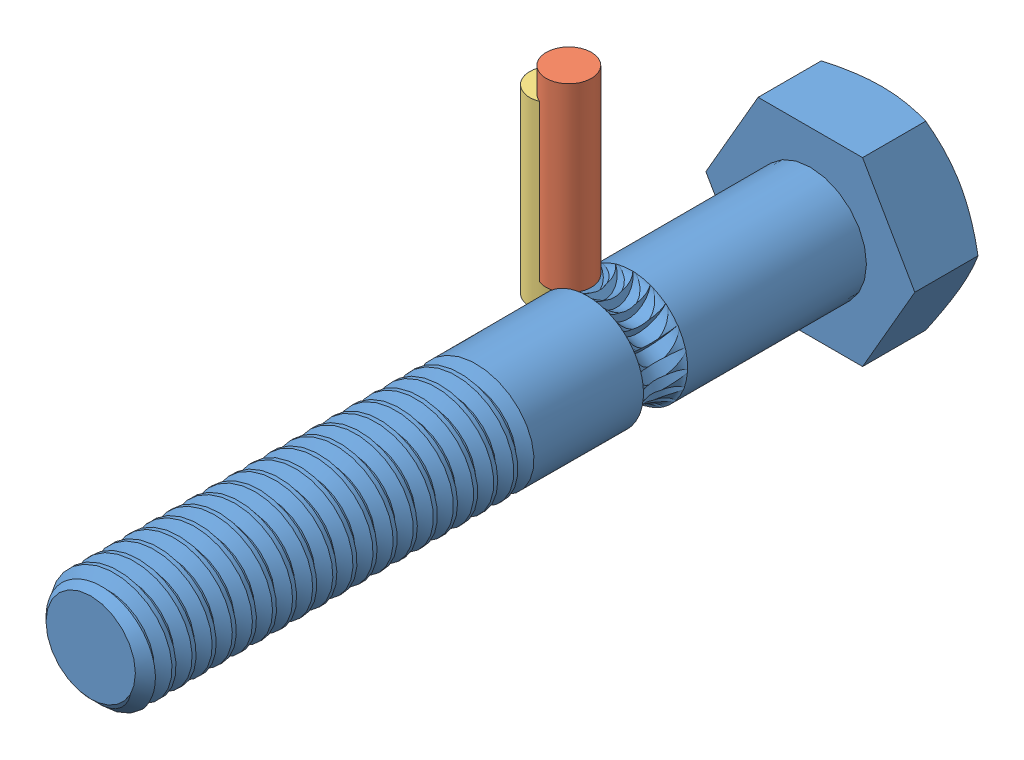
SolidWorks assembly HobbedBoltCutting, configuration Default. Lengths in mm.
Overall size (14.66 22.1 56.13).
3 component instances, 3 part files, 3 mates.
Components (placement in the parent):
- HobbedBolt-Model-1: HobbedBolt-Model [Default] at origin size (14.66 12.7 56.13)
- Waist Cutter^HobbedBoltCutting-1: Waist Cutter^HobbedBoltCutting [Default] at origin size (3.17 12.7 3.18) (virtual)
- Tooth Cutter^HobbedBoltCutting-1: Tooth Cutter^HobbedBoltCutting [Default] at origin size (3.17 12.7 3.18) (virtual)
Mates (geometry in assembly coordinates):
- Coincident1: coincident aligned: plane of HobbedBolt-Model-1 through (0 0 0) normal (0 0 1); plane of assembly through (0 0 0) normal (0 0 1)
- Coincident2: coincident aligned: plane of HobbedBolt-Model-1 through (0 0 0) normal (0 1 0); plane of assembly through (0 0 0) normal (0 1 0)
- Coincident3: coincident aligned: plane of HobbedBolt-Model-1 through (0 0 0) normal (1 0 0); plane of assembly through (0 0 0) normal (1 0 0)
